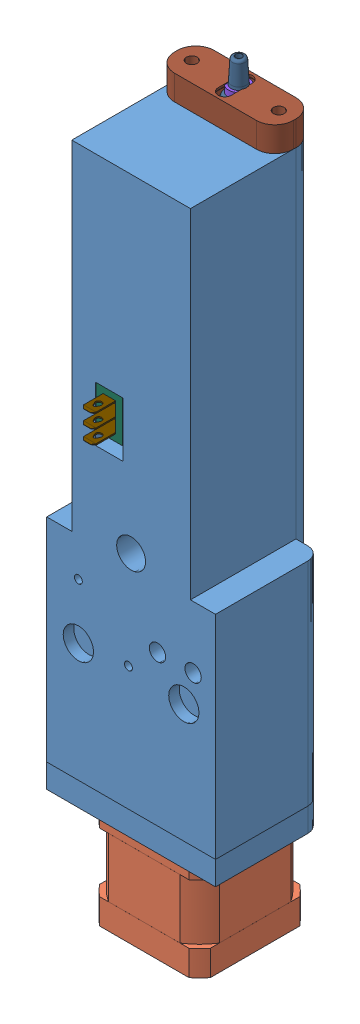
SolidWorks assembly SyringePumpAssembly, configuration Default. Lengths in mm.
Overall size (64 276.28 61.35).
25 component instances, 20 part files, 36 mates.
Components (placement in the parent):
- SyringePumpBaseV3-1: SyringePumpBaseV3 [Default] at (-22.5 -127.2 21) x (0 1 0) z (-1 0 0) size (209 47 64)
- [MoonsSteppers] Stepper Motor.step-1: [MoonsSteppers] Stepper Motor.step [Default] at (-17.6097 -167 -17.6003) size (42 63.8 48)
- [Misumi]MTSRA10_100_S30_Q6-1: [Misumi]MTSRA10_100_S30_Q6 [Default] at (0.0403 -3.2 0.0497) x (0 -1 0) z (0 0 1) size (100 10 10)
- [Misumi]MRGS_16_5_6-1: [Misumi]MRGS_16_5_6 [Default] at (0.0403 -115.2 0.0497) x (0 1 0) z (0 0 -1) size (24 16 16)
- [Misumi]MTSNR10-5: [Misumi]MTSNR10 [Default] at (0.0403 -27.6761 0.0497) x (0 -1 0) z (0 0 1) size (24 36 20)
- Syringe-1: Syringe [Default] at (0 50.1 -14.825) x (-0.999996 0 -0.002979) z (0 1 0) size (13.5 10.78 130.68) (flexible)
  - SyringeBase-1: SyringeBase [Default] at (-6.75 -5.25 -44.9) size (13.5 10.5 89.8)
  - Plunger-1: Plunger [Default] at (0 0 -80.7761) x (0.98462 -0.17471 0) z (0 0 1) size (9.3 9.3 99.2)
  - RNNut-1: RNNut [Default] at (0 0 44.9) x (0.397868 0.917443 0) z (0 0 1) size (7.8 7.8 5)
- PlungerHolder-4: PlungerHolder [Default] at (21.0403 -24.6761 12.0497) x (-1 0 0) z (0 -1 0) size (42 31 12)
- SyringePumpHolder-2: SyringePumpHolder [Default] at (0 -65.3481 28.5) x (1 0 0) z (0 0 -1) size (64 63.5 26.5) (hidden)
- 200uLTipAdapter-1: 200uLTipAdapter [Default] at (0 96.8 -14.825) x (0.999994 0 0.003546) z (-0.003546 0 0.999994) size (10.1 18.48 10.1)
- TipEjectorBottomEnd-3: TipEjectorBottomEnd [Default] at (22.5 90.7585 -6) x (-1 0 0) z (0 0 1) size (45 9.5 15)
- TipEjectorTopEnd-2: TipEjectorTopEnd [Default] at (20.9972 -19.7415 -5.9862) x (-1 0 -0.000367) z (-0.000367 0 1) size (42 9.5 15)
- TipEjectorShaft-1: TipEjectorShaft [Default] at (-16.5 -15.2415 -13.5) x (0.999903 0 0.013903) z (-0.013903 0 0.999903) size (3.9 108 3.9)
- TipEjectorShaft-2: TipEjectorShaft [Default] at (16.5 -15.2415 -13.5) x (-0.999467 0 -0.032648) z (0.032648 0 -0.999467) size (3.9 108 3.9)
- [CIT Relay & Switch] VM3SCQF1802L03-3: [CIT Relay & Switch] VM3SCQF1802L03 [Default] at (-13.25 8.2435 4.8413) x (1 0 0) z (0 -1 0) size (10.4 50.82 20.74)
  - VM3_Solid Body.stp-1: VM3_Solid Body.stp [Default] at origin size (10.4 28.01 15.81)
  - VM3_End Cap2.stp-1: VM3_End Cap2.stp [Default] at (9.9 20.9587 0.9078) x (-1 0 0) z (0 0 -1) size (9.9 7.5 15.8)
  - Rubber Boot Push Button.stp-1: Rubber Boot Push Button.stp [Default] at (4.95 -6.3413 5.0935) x (-0.122747 -0.992438 0) z (0 0 1) size (9.25 9.25 6)
  - L88.stp-1: L88.stp [Default] at (9.55 7.7381 10.2524) x (0 -0.994711 0.102715) z (-1 0 0) size (35.16 6.04 8.6)
  - VM3S_TERMINAL_TEARDROP.stp-1: VM3S_TERMINAL_TEARDROP.stp [Default] at (4.95 16.5587 -0.0065) x (0 1 0) z (1 0 0) size (13 0.5 4.75)
  - VM3S_TERMINAL_TEARDROP.stp-2: VM3S_TERMINAL_TEARDROP.stp [Default] at (4.95 16.5587 5.6935) x (0 1 0) z (-1 0 0) size (13 0.5 4.75)
  - VM3S_TERMINAL_TEARDROP.stp-3: VM3S_TERMINAL_TEARDROP.stp [Default] at (4.95 16.5587 -5.2065) x (0 1 0) z (1 0 0) size (13 0.5 4.75)
- MotorHolder-1: MotorHolder [Default] at (0 -127.2 8.5) size (64 9 47)
Mates (geometry in assembly coordinates):
- Coincident1: coincident anti-aligned: plane of SyringePumpBaseV3-1 through (-22.5 0 21) normal (0 -1 0)
- Coincident2: coincident anti-aligned: plane of SyringePumpBaseV3-1 through (-22.5 -127.2 0) normal (0 0 -1)
- Coincident3: coincident anti-aligned: plane of SyringePumpBaseV3-1 through (0 -127.2 21) normal (-1 0 0)
- Coincident6: coincident aligned: plane of [MoonsSteppers] Stepper Motor.step-1 through (0.0403 -103.2 0.0497) normal (0 1 0); plane of [Misumi]MRGS_16_5_6-1 through (2.5403 -103.2 0.0497) normal (0 1 0)
- Concentric1: concentric anti-aligned: cylinder of [Misumi]MTSRA10_100_S30_Q6-1 through (0.0403 -103.2 0.0497) axis (0 -1 0) radius 3; cylinder of [Misumi]MRGS_16_5_6-1 through (0.0403 -91.2 0.0497) axis (0 1 0) radius 3
- Coincident9: coincident anti-aligned: plane of [Misumi]MTSRA10_100_S30_Q6-1 through (2.5403 -103.2 0.0497) normal (0 -1 0); plane of [Misumi]MRGS_16_5_6-1 through (2.5403 -103.2 0.0497) normal (0 1 0)
- Concentric7: concentric aligned: cylinder of [MoonsSteppers] Stepper Motor.step-1 through (0.0403 -132.2 0.0497) axis (0 1 0) radius 2.5; cylinder of [Misumi]MRGS_16_5_6-1 through (0.0403 -91.2 0.0497) axis (0 1 0) radius 2.5
- Coincident10: coincident anti-aligned: plane of MotorHolder-1 through (27 -127.2 -9) normal (0 -1 0); plane of [MoonsSteppers] Stepper Motor.step-1 through (0.0403 -127.2 0.0497) normal (0 1 0)
- Concentric19: concentric anti-aligned: circle of [MoonsSteppers] Stepper Motor.step-1; circle of MotorHolder-1
- Coincident12: coincident anti-aligned: plane of SyringePumpBaseV3-1 through (7 8 -8.5) normal (0 -1 0); plane of Syringe-1/SyringeBase-1 through (6.7656 8 -20.0549) normal (0 1 0)
- Concentric16: concentric anti-aligned: circle of [Misumi]MTSNR10-5; cylinder of PlungerHolder-4 through (13.0403 -17.6761 0.0497) axis (0 -1 0) radius 2.15
- Concentric17: concentric anti-aligned: cylinder of [Misumi]MTSNR10-5 through (-12.9597 -27.6761 0.0497) axis (0 1 0) radius 2.15; circle of Plunger Holder-4
- Coincident24: coincident anti-aligned: plane of [Misumi]MTSNR10-5 through (0.0403 -27.6761 0.0497) normal (0 1 0); plane of PlungerHolder-4 through (0.0403 -27.6761 0.0497) normal (0 -1 0)
- Coincident25: coincident anti-aligned: plane of Syringe-1/Plunger-1 through (0 -30.6761 -14.825) normal (0 -1 0); plane of PlungerHolder-4 through (-4.6097 -30.6761 -10.6703) normal (0 1 0)
- Concentric21: concentric anti-aligned: cylinder of [Misumi]MTSRA10_100_S30_Q6-1 through (0.0403 -73.2 0.0497) axis (0 -1 0) radius 5; cylinder of [Misumi]MTSNR10-5 through (0.0403 -27.6761 0.0497) axis (0 1 0) radius 4
- Concentric22: concentric aligned: cylinder of Syringe-1/RNNut-1 through (0 100 -14.825) axis (0 -1 0) radius 3.9; cylinder of 200uLTipAdapter-1 through (0 -903.2 -14.825) axis (0 -1 0) radius 3.95
- Coincident29: coincident anti-aligned: plane of SyringePumpBaseV3-1 through (-22.5 90.8 -21) normal (0 1 0); plane of 200uLTipAdapter-1 through (-5.05 90.8 -14.8429) normal (0 -1 0)
- Coincident35: coincident anti-aligned: plane of SyringePumpBaseV3-1 through (-22.5 -127.2 26) normal (0 0 1); plane of SyringePumpHolder-2 through (0 -65.3481 26) normal (0 0 -1)
- Concentric27: concentric anti-aligned: circle of 200uLTipEjectorBottomEnd-3; circle of TipEjectorShaft-2
- Concentric28: concentric anti-aligned: cylinder of SyringePumpBaseV3-1 through (0 -7 -14.825) axis (0 1 0) radius 3.875; cylinder of Syringe-1/SyringeBase-1 through (0 95 -14.825) axis (0 -1 0) radius 3.875
- Concentric29: concentric anti-aligned: cylinder of SyringePumpBaseV3-1 through (-16.5 -4.2 -13.5) axis (0 1 0) radius 2.1; cylinder of TipEjectorShaft-1 through (-16.5 92.7585 -13.5) axis (0 -1 0) radius 1.95
- Concentric30: concentric anti-aligned: cylinder of SyringePumpBaseV3-1 through (16.5 -4.2 -13.5) axis (0 1 0) radius 2.1; cylinder of TipEjectorShaft-2 through (16.5 92.7585 -13.5) axis (0 -1 0) radius 1.95
- Concentric32: concentric anti-aligned: circle of TipEjectorBottomEnd-3; circle of TipEjectorShaft-1
- Coincident39: coincident anti-aligned: plane of 200uLTipEjectorBottomEnd-3 through (-16.5 92.7585 -13.5) normal (0 -1 0); plane of TipEjectorShaft-1 through (-16.5 92.7585 -13.5) normal (0 1 0)
- Coincident40: coincident anti-aligned: plane of 200uLTipEjectorBottomEnd-3 through (16.5 92.7585 -13.5) normal (0 -1 0); plane of TipEjectorShaft-2 through (16.5 92.7585 -13.5) normal (0 1 0)
- Concentric35: concentric aligned: circle of TipEjectorTopEnd-2; circle of TipEjectorShaft-1
- Coincident43: coincident anti-aligned: plane of TipEjectorTopEnd-2 through (-16.5 -15.2415 -13.5) normal (0 1 0); plane of TipEjectorShaft-1 through (-16.5 -15.2415 -13.5) normal (0 -1 0)
- Coincident54: coincident anti-aligned: plane of SyringePumpBaseV3-1 through (-22.5 -127.2 -6.15) normal (0 0 1); plane of [CIT Relay & Switch] VM3SCQF1802L03.stp-3/VM3_Solid Body.stp-1 through (-13.25 0 -6.15) normal (0 0 -1)
- Coincident56: coincident anti-aligned: plane of SyringePumpBaseV3-1 through (-3.1 0 -6.15) normal (-1 0 0); plane of [CIT Relay & Switch] VM3SCQF1802L03.stp-3/VM3_Solid Body.stp-1 through (-3.1 2.3712 19.3873) normal (1 0 0)
- Coincident57: coincident anti-aligned: plane of SyringePumpBaseV3-1 through (-3.1 15.8 -6.15) normal (0 -1 0); plane of [CIT Relay & Switch] VM3SCQF1802L03.stp-3/VM3_End Cap2.stp-1 through (-3.35 15.8 26) normal (0 1 0)
- Coincident58: coincident aligned: line of SyringePumpBaseV3-1 through (32 -118.2 26) axis (0 0 -1); line of MotorHolder-1 through (32 -118.2 26) axis (0 0 -1)
- Coincident59: coincident anti-aligned: line of SyringePumpBaseV3-1 through (-32 -118.2 26) axis (0 0 -1); line of MotorHolder-1 through (-32 -118.2 -9) axis (0 0 1)
- Coincident60: coincident aligned: line of SyringePumpBaseV3-1 through (-32 -118.2 26) axis (1 0 0); line of MotorHolder-1 through (-32 -118.2 26) axis (1 0 0)
- Parallel3: parallel aligned: line of [MoonsSteppers] Stepper Motor.step-1 through (17.0108 -127.2 -20.9503) axis (-1 0 0); line of MotorHolder-1 through (15.5 -127.2 -21) axis (-1 0 0)
- Coincident61: coincident anti-aligned: line of SyringePumpBaseV3-1 through (32 -118.2 26) axis (0 1 0); line of SyringePumpHolder-2 through (32 -37.7 26) axis (0 -1 0)
- Coincident62: coincident aligned: line of SyringePumpBaseV3-1 through (32 -37.7 26) axis (-1 0 0); line of SyringePumpHolder-2 through (32 -37.7 26) axis (-1 0 0)
